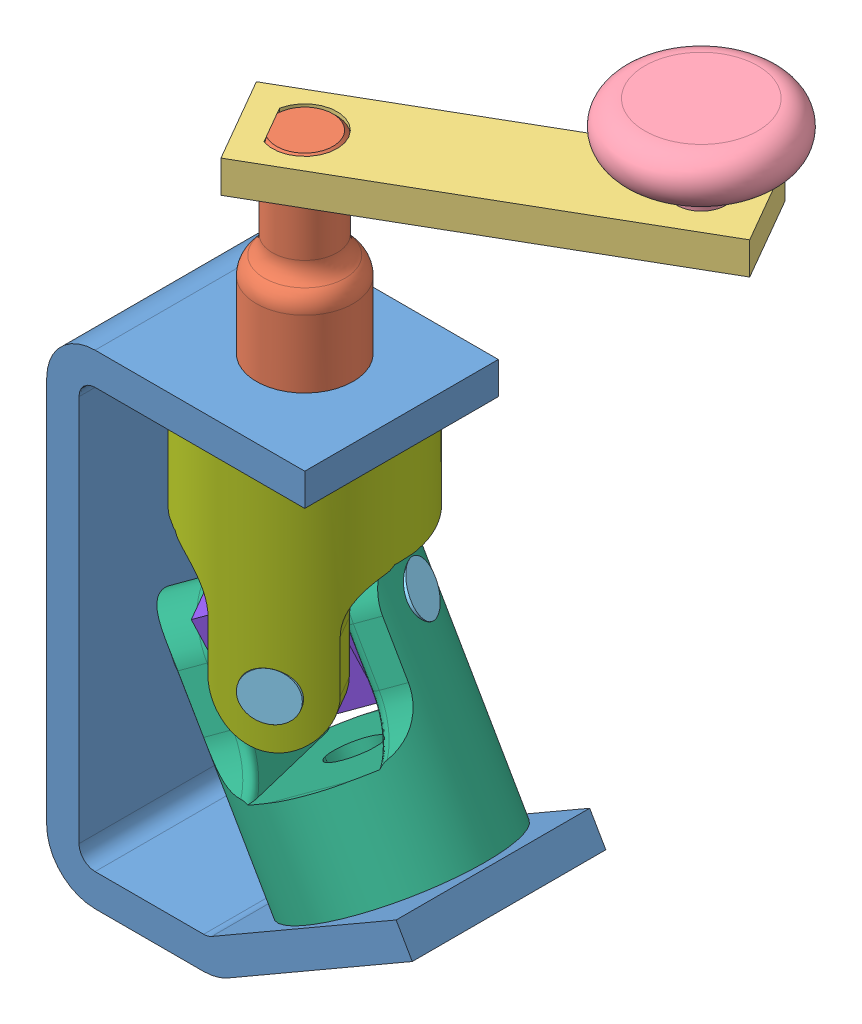
SolidWorks assembly u-joint, configuration Default. Lengths in mm.
Overall size (111.85 150.22 85.21).
11 component instances, 8 part files, 20 mates.
Components (placement in the parent):
- bracket_&-1: bracket_& [Default] x (0 0 -1) z (1 0 0) size (38.1 95.25 71.97)
- crank-assy_&-1: crank-assy_& [Default] at (25.4 89.9 0) x (-0.866025 0 0.5) z (-0.5 0 -0.866025) size (89.08 53.98 44.81)
  - crank-shaft_&-1: crank-shaft_& [Default] at origin size (19.05 38.1 19.05)
  - crank-arm_&-1: crank-arm_& [Default] at (-66.675 31.75 -9.525) size (76.2 6.35 19.05)
  - test-practicecrank-knob_&-1: test-practicecrank-knob_& [Default] at (-57.15 31.75 0) x (0.661436 0 -0.750001) z (0.750001 0 0.661436) size (31.75 22.23 31.75)
- pin_&-1: pin_& [Long] at (34.925 44.45 16.4978) x (-0.866025 0.000004 0.5) z (-0.5 0 -0.866025) size (9.53 9.53 38.1)
- test-practiceYoke_female_&-1: test-practiceYoke_female_& [Default] at (20.6375 52.6989 0) x (0.387298 0.223607 0.894427) z (0.774597 0.447214 -0.447214) size (38.1 47.62 38.1)
- Yoke_male_&-1: Yoke_male_& [Default] at (25.4 34.925 0) x (-0.866025 0 0.5) z (-0.5 0 -0.866025) size (38.1 66.67 38.1)
- pin_&-2: pin_& [Short] at (10.6439 35.9306 8.5194) x (-0.597833 0.286989 -0.748488) z (0.774597 0.447214 -0.447214) size (9.53 9.53 12.7)
- pin_&-3: pin_& [Short] at (40.1561 52.9694 -8.5194) x (0.527413 -0.066505 0.847002) z (-0.774597 -0.447214 0.447214) size (9.53 9.53 12.7)
- spider_&-2: spider_& [Default] at (25.4 44.45 0) x (0.774597 0.447214 -0.447214) z (-0.5 0 -0.866025) size (20.32 20.32 20.32)
Mates (geometry in assembly coordinates):
- Concentric1: concentric anti-aligned: cylinder of bracket_&-1 through (25.4 -6.351 0) axis (0 1 0) radius 6.35; cylinder of Yoke_male_&-1 through (25.4 101.6 0) axis (0 -1 0) radius 6.35
- Coincident5: coincident anti-aligned: plane of bracket_&-1 through (3.175 82.55 -19.05) normal (0 -1 0); plane of Yoke_male_&-1 through (25.4 82.55 0) normal (0 1 0)
- Concentric2: concentric anti-aligned: cylinder of pin_&-1 through (15.875 44.45 -16.4978) axis (0.5 0 0.866025) radius 4.7625; cylinder of Yoke_male_&-1 through (34.925 44.45 16.4978) axis (-0.5 0 -0.866025) radius 4.7625
- Width1: width anti-aligned: plane of Yoke_male_&-1 through (36.8178 27.4697 -18.3238) normal (0.5 0 0.866025); plane of Yoke_male_&-1 through (46.9778 64.0702 -0.7262) normal (-0.5 0 -0.866025); plane of pin_&-1 through (15.875 44.45 -16.4978) normal (-0.5 0 -0.866025); plane of pin_&-1 through (34.925 44.45 16.4978) normal (0.5 0 0.866025)
- Coincident8: coincident anti-aligned: plane of crank-assy_&-1/crank-shaft_&-1 through (19.1755 102.6 -1.2562) normal (0.866025 0 -0.5); plane of Yoke_male_&-1 through (19.1755 88.9 -1.2562) normal (-0.866025 0 0.5)
- Coincident16: coincident anti-aligned: cylinder of pin_&-1 through (15.875 44.45 -16.4978) axis (0.5 0 0.866025) radius 4.7625; circle of spider_&-2
- Coincident17: coincident anti-aligned: plane of Yoke_male_&-1 through (46.9778 64.0702 -0.7262) normal (-0.5 0 -0.866025); plane of spider_&-2 through (26.545 30.8189 11.0707) normal (0.5 0 0.866025)
- Concentric3: concentric anti-aligned: cylinder of pin_&-2 through (19.2516 40.9002 3.5498) axis (-0.774597 -0.447214 0.447214) radius 4.7625; cylinder of spider_&-2 through (17.5301 39.9063 4.5437) axis (0.774597 0.447214 -0.447214) radius 4.7625
- Concentric9: concentric aligned: cylinder of pin_&-3 through (29.089 46.5799 -2.1299) axis (0.774597 0.447214 -0.447214) radius 4.7625; cylinder of spider_&-2 through (17.5301 39.9063 4.5437) axis (0.774597 0.447214 -0.447214) radius 4.7625
- Distance3: distance = 1 mm anti-aligned: plane of crank-assy_&-1/crank-shaft_&-1 through (25.4 102.6 0) normal (0 -1 0); plane of Yoke_male_&-1 through (25.4 101.6 0) normal (0 1 0)
- Concentric14: concentric aligned: cylinder of crank-assy_&-1/crank-shaft_&-1 through (25.4 102.6 0) axis (0 -1 0) radius 6.35; cylinder of Yoke_male_&-1 through (25.4 101.6 0) axis (0 -1 0) radius 6.35
- Coincident31: coincident: point of bracket_&-1; point of assembly
- Parallel12: parallel aligned: plane of bracket_&-1 through (3.175 79.375 19.05) normal (0 0 1); plane of assembly through (0 0 0) normal (0 0 1)
- Coincident39: coincident aligned: plane of bracket_&-1 through (24.5493 0 -19.05) normal (0 1 0); plane of assembly through (0 0 0) normal (0 1 0)
- Concentric15: concentric aligned: cylinder of test-practiceYoke_female_&-1 through (9.4143 35.2206 9.2294) axis (0.774597 0.447214 -0.447214) radius 4.7625; cylinder of pin_&-3 through (29.089 46.5799 -2.1299) axis (0.774597 0.447214 -0.447214) radius 4.7625
- Tangent10: tangent aligned: cylinder of test-practiceYoke_female_&-1 through (43.2203 10.7445 0.71) axis (-0.5 0.866025 0) radius 19.05; plane of pin_&-3 through (38.9264 52.2595 -7.8095) normal (0.774597 0.447214 -0.447214)
- Parallel14: parallel anti-aligned: plane of bracket_&-1 through (62.443 21.3868 -19.05) normal (-0.5 0.866025 0); plane of test-practiceYoke_female_&-1 through (43.2203 10.7445 0.71) normal (0.5 -0.866025 0)
- Angle1: planar angle = 0.523599 rad aligned: plane of bracket_&-1 through (3.175 79.375 19.05) normal (0 0 1); plane of crank-assy_&-1/crank-arm_&-1 through (87.9047 121.65 -25.0886) normal (0.5 0 0.866025)
- Tangent14: tangent aligned: cylinder of test-practiceYoke_female_&-1 through (43.2203 10.7445 0.71) axis (-0.5 0.866025 0) radius 19.05; plane of pin_&-2 through (9.4143 35.2206 9.2294) normal (-0.774597 -0.447214 0.447214)
- Width6: width: plane of test-practiceYoke_female_&-1 through (62.1545 43.0147 84.9439) normal (0.774597 0.447214 -0.447214); plane of test-practiceYoke_female_&-1 through (63.3217 77.3426 75.8566) normal (-0.774597 -0.447214 0.447214); cylinder of pin_&-1 through (15.875 44.45 -16.4978) axis (0.5 0 0.866025) radius 4.7625
